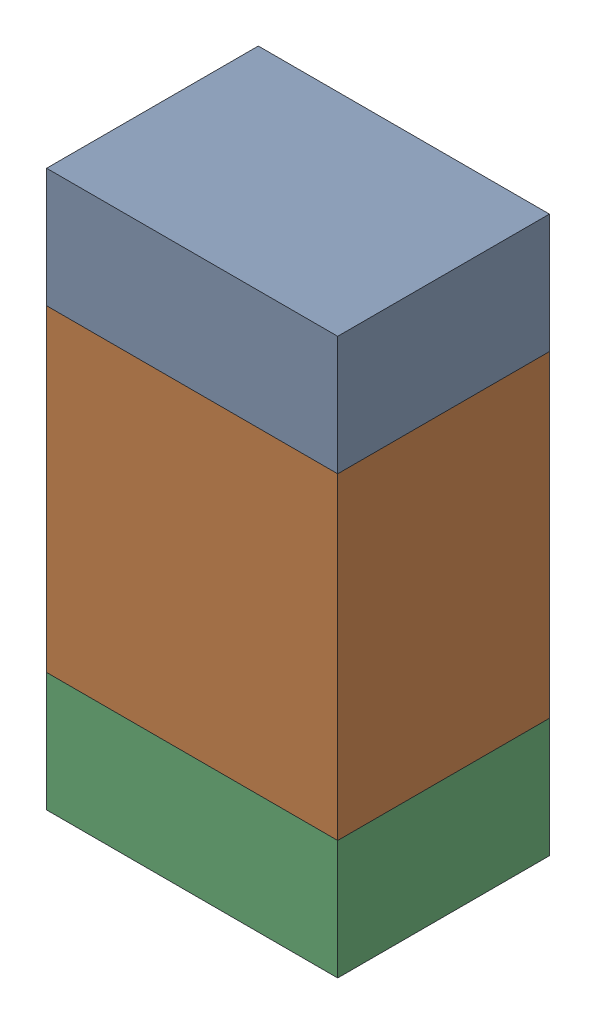
SolidWorks assembly R501_2PCB, configuration Default. Lengths in mm.
Overall size (0.55 1.05 0.4).
6 component instances, 2 part files, 0 mates.
Components (placement in the parent):
- 846483288-1: 846483288 [Default] at (152.6501 85.9124 0) size (0.55 0.22 0.4)
  - Extruded_12-1: Extruded_12 [Default] at origin size (0.55 0.22 0.4)
- 846483424-1: 846483424 [Default] at (152.6501 85.4999 0) size (0.55 0.6 0.4)
  - Extruded_13-1: Extruded_13 [Default] at origin size (0.55 0.6 0.4)
- 846483288-2: 846483288 [Default] at (152.6501 85.0874 0) size (0.55 0.22 0.4)
  - Extruded_12-1: Extruded_12 [Default] at origin size (0.55 0.22 0.4)
